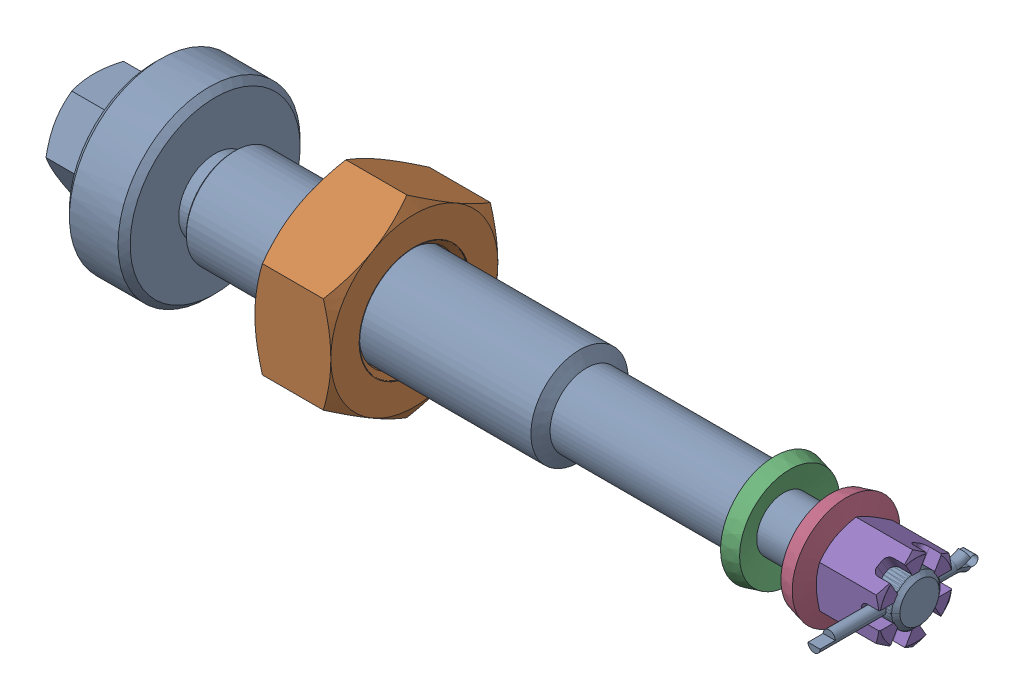
SolidWorks assembly g1_3_1_1_7, configuration 默认. Lengths in mm.
Overall size (272.02 63.51 60).
6 component instances, 5 part files, 0 mates.
Components (placement in the parent):
- g1_3_1_1_7-1-1: g1_3_1_1_7-1 [默认] at origin size (272.02 60 60)
- g1_3_1_1_7-2-1: g1_3_1_1_7-2 [默认] at (-104.3833 -31.7543 0) x (0 1 0) z (1 0 0) size (63.51 55 25)
- 4x40_gb91-1: 4x40_gb91 [默认] at (82.0173 -2 29.7543) x (0 0 1) z (-1 -0.000312 0) size (52 6.04 4)
- a35_5_gb1972-1: a35_5_gb1972 [默认] at (39.2167 0 0) x (0 0.075145 0.997173) z (0 0.997173 -0.075145) size (35.5 7.2 35.5)
- a35_5_gb1972-2: a35_5_gb1972 [默认] at (62.8167 0 0) x (0 -0.99777 0.066751) z (0 -0.066751 -0.99777) size (35.5 7.2 35.5)
- m16a_gb6178-1: m16a_gb6178 [默认] at (85.8167 13.8564 0) x (0 -1 0) z (-1 0 0) size (27.71 24 20.8)
